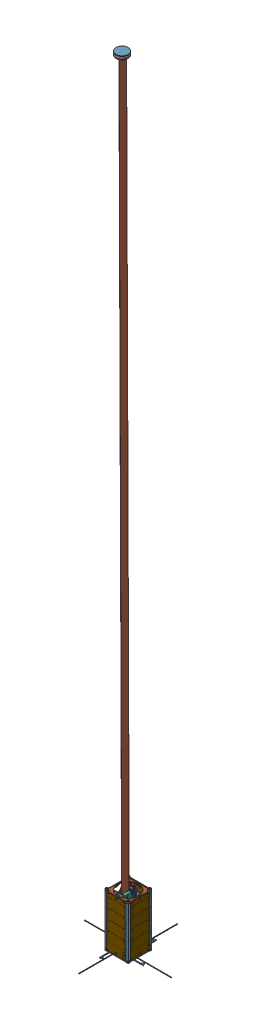
SolidWorks assembly FullAssembly_Deployed_Render, configuration Default. Lengths in mm.
Overall size (392.46 3272.78 392.43).
161 component instances, 59 part files, 152 mates.
Components (placement in the parent):
- 2U_Chassis_NoEnds-1: 2U_Chassis_NoEnds [Default] at (129.3638 156.9234 217.0115) size (100 209.95 100)
- FirstAdapterPlate-1: FirstAdapterPlate [Default] at (79.3638 3.0787 167.0115) size (95.9 1.58 90.2)
- 5-40_nut-9: 5-40_nut [90760A130] at (36.5138 -0.4932 127.0115) size (6.35 2.87 7.33)
- 5-40_nut-10: 5-40_nut [90760A130] at (36.5138 1.888 127.0115) x (-0.837169 0 -0.546944) z (-0.546944 0 0.837169) size (6.35 2.87 7.33)
- ThreadedRod_1.25mm_2-1: ThreadedRod_1.25mm_2 [94435A506] at (122.2138 23.2162 204.5115) x (0 -1 0) z (0 0 1) size (64.19 3.19 3.69)
- ThreadedRod_1.25mm_2-2: ThreadedRod_1.25mm_2 [94435A506] at (36.5138 23.2162 127.0115) x (0 -1 0) z (0 0 1) size (64.19 3.19 3.69)
- ThreadedRod_1.25mm_2-3: ThreadedRod_1.25mm_2 [94435A506] at (122.2138 23.2162 130.8115) x (0 -1 0) z (0 0 1) size (64.19 3.19 3.69)
- ThreadedRod_1.25mm_2-4: ThreadedRod_1.25mm_2 [94435A506] at (36.5138 23.2162 207.0115) x (0 -1 0) z (0 0 1) size (64.19 3.19 3.69)
- 5-40_nut-11: 5-40_nut [90760A130] at (36.5138 1.888 207.0115) x (-0.837169 0 -0.546944) z (-0.546944 0 0.837169) size (6.35 2.87 7.33)
- 5-40_nut-12: 5-40_nut [90760A130] at (36.5138 -0.4932 207.0115) x (-1 0 0) z (0 0 -1) size (6.35 2.87 7.33)
- 5-40_nut-13: 5-40_nut [90760A130] at (122.2138 14.9255 204.5115) x (0.837169 0 0.546944) z (0.546944 0 -0.837169) size (6.35 2.87 7.33)
- 5-40_nut-14: 5-40_nut [90760A130] at (122.2138 12.5443 204.5115) x (-0.540526 0 0.841327) z (-0.841327 0 -0.540526) size (6.35 2.87 7.33)
- 5-40_nut-15: 5-40_nut [90760A130] at (122.2138 14.9255 130.8115) x (0.837169 0 0.546944) z (0.546944 0 -0.837169) size (6.35 2.87 7.33)
- 5-40_nut-16: 5-40_nut [90760A130] at (122.2138 12.5443 130.8115) x (-1 0 0) z (0 0 -1) size (6.35 2.87 7.33)
- 5-40_nut-17: 5-40_nut [90760A130] at (36.5138 12.5443 207.0115) x (-1 0 0) z (0 0 -1) size (6.35 2.87 7.33)
- 5-40_nut-18: 5-40_nut [90760A130] at (36.5138 14.9255 127.0115) x (0.861208 0 0.508253) z (0.508253 0 -0.861208) size (6.35 2.87 7.33)
- 5-40_nut-19: 5-40_nut [90760A130] at (122.2138 -0.4932 204.5115) x (-1 0 0) z (0 0 -1) size (6.35 2.87 7.33)
- 5-40_nut-20: 5-40_nut [90760A130] at (36.5138 12.5443 127.0115) x (-1 0 0) z (0 0 -1) size (6.35 2.87 7.33)
- 5-40_nut-21: 5-40_nut [90760A130] at (122.2138 -0.4932 130.8115) x (-1 0 0) z (0 0 -1) size (6.35 2.87 7.33)
- 5-40_nut-22: 5-40_nut [90760A130] at (122.2138 1.888 130.8115) x (-0.837169 0 -0.546944) z (-0.546944 0 0.837169) size (6.35 2.87 7.33)
- 5-40_nut-23: 5-40_nut [90760A130] at (122.2138 1.888 204.5115) x (-0.837169 0 -0.546944) z (-0.546944 0 0.837169) size (6.35 2.87 7.33)
- 5-40_nut-24: 5-40_nut [90760A130] at (36.5138 14.9255 207.0115) x (0.837169 0 0.546944) z (0.546944 0 -0.837169) size (6.35 2.87 7.33)
- Endurosat_Internal-1: Endurosat_Internal [Default] at (43.9577 -28.9874 233.1363) x (1 0 0) z (0 1 0) size (98.18 90.37 51.86)
  - UHF_comm_type_II.STEP-1: UHF_comm_type_II.STEP [Default] at (27.1151 12.3666 -17.6788) size (97.88 89.01 26.68)
    - UHF_BOX.STEP-1: UHF_BOX.STEP [Default] at (-90.205 -23.549 76.8824) size (95 89 8.01)
    - UHF_PCB_STEP.STEP-1: UHF_PCB_STEP.STEP [Default] at (-39.659 9.6582 83.8824) size (97.88 89.01 26.68)
    - UHF_BOX-bottom-part(nif).STEP-1: UHF_BOX-bottom-part(nif).STEP [Default] at (-24.9069 125.9519 81.8824) x (1 0 0) z (0 -1 0) size (95 2.01 89)
  - OBC_EnduroSat.STEP-1: OBC_EnduroSat.STEP [Default] at (-12.5439 22.0248 80.3036) x (1 0 0) z (0 0 1) size (95 89.38 23.24)
    - SD1021117.STEP-1: SD1021117.STEP [Default] at origin size (15.2 14.1 1.88)
      - User_Library-473521001_microSD.STEP-1: User_Library-473521001_microSD.STEP [Default] at (11.4631 39.834 0.9) x (0 -1 0) z (0 0 1) size (14.1 15.2 1.88)
    - P1021117.STEP-1: P1021117.STEP [Default] at origin size (10.15 5.2 3.4)
      - MOLEX_Pico_Blade_532610471.STEP-1: MOLEX_Pico_Blade_532610471.STEP [Default] at (43.8404 79.9325 1.7) size (10.15 5.2 3.4)
        - Open CASCADE STEP translator 6.8 1.14.1.1.STEP-1: Open CASCADE STEP translator 6.8 1.14.1.1.STEP [Default] at origin size (10.15 5.2 3.4)
    - USB1021117.STEP-1: USB1021117.STEP [Default] at origin size (9.9 9.22 5.09)
      - USB_Mini_B_SMT_Horisontal.STEP-1: USB_Mini_B_SMT_Horisontal.STEP [Default] at (43.8628 84.9308 -3.6122) x (1 0 0) z (0 1 0) size (9.9 5.09 9.22)
    - U1021117.STEP-1: U1021117.STEP [Default] at origin size (25.77 25.77 1.57)
      - User_Library-LQFP176-0_5.STEP-1: User_Library-LQFP176-0_5.STEP [Default] at (45.653 34.1752 0.75) x (1 0 0) z (0 0 1) size (25.77 25.77 1.57)
    - PAN6021117.STEP-1: PAN6021117.STEP [Default] at origin size (20.15 5.2 3.5)
      - MOLEX_Pico_Blade_532611271.STEP-1: MOLEX_Pico_Blade_532611271.STEP [Default] at (74.0242 8.708 -1.6) x (-1 0 0) z (0 0 -1) size (20.15 5.2 3.5)
    - PAN5021117.STEP-1: PAN5021117.STEP [Default] at origin size (20.15 5.2 3.5)
      - MOLEX_Pico_Blade_532611271.STEP-1: MOLEX_Pico_Blade_532611271.STEP [Default] at (46.9392 8.708 -1.6) x (-1 0 0) z (0 0 -1) size (20.15 5.2 3.5)
    - PAN4021117.STEP-1: PAN4021117.STEP [Default] at origin size (20.15 5.2 3.5)
      - MOLEX_Pico_Blade_532611271.STEP-1: MOLEX_Pico_Blade_532611271.STEP [Default] at (19.8882 8.708 -1.6) x (-1 0 0) z (0 0 -1) size (20.15 5.2 3.5)
    - PAN3021117.STEP-1: PAN3021117.STEP [Default] at origin size (20.15 5.2 3.5)
      - MOLEX_Pico_Blade_532611271.STEP-1: MOLEX_Pico_Blade_532611271.STEP [Default] at (73.9902 8.708 0) x (1 0 0) z (0 0 1) size (20.15 5.2 3.5)
    - PAN2021117.STEP-1: PAN2021117.STEP [Default] at origin size (20.15 5.2 3.5)
      - MOLEX_Pico_Blade_532611271.STEP-1: MOLEX_Pico_Blade_532611271.STEP [Default] at (46.9392 8.708 0) size (20.15 5.2 3.5)
    - PAN1021117.STEP-1: PAN1021117.STEP [Default] at origin size (20.15 5.2 3.5)
      - MOLEX_Pico_Blade_532611271.STEP-1: MOLEX_Pico_Blade_532611271.STEP [Default] at (19.8882 8.708 0) size (20.15 5.2 3.5)
    - H2021117.STEP-1: H2021117.STEP [Default] at origin size (5.08 66.55 23.24)
      - Samtec-ESQ-126-14-G-D.STEP-1: Samtec-ESQ-126-14-G-D.STEP [Default] at (89.5246 43.45 2.5522) x (-1 0 0) z (0 1 0) size (5.08 23.24 66.55)
    - H1021117.STEP-1: H1021117.STEP [Default] at origin size (5.08 66.55 23.24)
      - Samtec-ESQ-126-14-G-D.STEP-1: Samtec-ESQ-126-14-G-D.STEP [Default] at (84.4446 43.45 2.5522) x (-1 0 0) z (0 1 0) size (5.08 23.24 66.55)
    - J1021117.STEP-1: J1021117.STEP [Default] at origin size (10.55 6.44 2)
      - 5040500491.STEP-1: 5040500491.STEP [Default] at (55.0672 77.863 1) x (1 0 0) z (0 0 1) size (10.55 6.44 2)
        - Open CASCADE STEP translator 6.8 1.245.1.1.STEP-1: Open CASCADE STEP translator 6.8 1.245.1.1.STEP [Default] at origin size (10.55 6.44 2)
    - JP2021117.STEP-1: JP2021117.STEP [Default] at origin size (5.56 20 4.5)
      - Samtec-TLE-110-01-G-DV.STEP-1: Samtec-TLE-110-01-G-DV.STEP [Default] at (68.9102 66.945 2.0874) x (0 1 0) z (1 0 0) size (20 4.5 5.56)
    - JP14021117.STEP-1: JP14021117.STEP [Default] at origin size (5.56 20 4.5)
      - Samtec-TLE-110-01-G-DV.STEP-1: Samtec-TLE-110-01-G-DV.STEP [Default] at (68.8848 66.945 -3.6873) x (0 1 0) z (-1 0 0) size (20 4.5 5.56)
    - JP15021117.STEP-1: JP15021117.STEP [Default] at origin size (20.15 4.2 4.7)
      - User_Library-molex_53398_1271.STEP-1: User_Library-molex_53398_1271.STEP [Default] at (19.1599 50.8269 0) x (1 0 0) z (0 0 1) size (20.15 4.2 4.7)
    - Board021117.STEP-1: Board021117.STEP [Default] at origin size (95 89.38 1.6)
  - EPS1 - Battery.STEP-1: EPS1 - Battery.STEP [Default] at (10.3437 18.3225 -33.4897) x (1 0 0) z (0 0 1) size (95.9 90.21 21.2)
    - ESQ_126_37_G_D.STEP-1: ESQ_126_37_G_D.STEP [Default] at (61.557 47.1532 82.7332) x (0 1 0) z (1 0 0) size (66.55 13.33 5.08)
      - _ESQ_126_37_G_D_socket_2.STEP-1: _ESQ_126_37_G_D_socket_2.STEP [Default] at (-33.274 0 0) size (66.55 8.51 4.95)
      - _ESQ_126_37_G_D_pins_4.STEP-1: _ESQ_126_37_G_D_pins_4.STEP [Default] at origin size (65.79 9.77 4.7)
      - _ESQ_126_37_G_D_LL_bpins_6.STEP-1: _ESQ_126_37_G_D_LL_bpins_6.STEP [Default] at (-33.147 -2.54 0) size (66.04 2.54 5.08)
    - ESQ_126_37_G_D.STEP-2: ESQ_126_37_G_D.STEP [Default] at (66.637 47.1532 82.7332) x (0 1 0) z (1 0 0) size (66.55 13.33 5.08)
      - _ESQ_126_37_G_D_socket_2.STEP-1: _ESQ_126_37_G_D_socket_2.STEP [Default] at (-33.274 0 0) size (66.55 8.51 4.95)
      - _ESQ_126_37_G_D_pins_4.STEP-1: _ESQ_126_37_G_D_pins_4.STEP [Default] at origin size (65.79 9.77 4.7)
      - _ESQ_126_37_G_D_LL_bpins_6.STEP-1: _ESQ_126_37_G_D_LL_bpins_6.STEP [Default] at (-33.147 -2.54 0) size (66.04 2.54 5.08)
    - ES_EPS_Rev1_4_PCB_STEP.STEP-1: ES_EPS_Rev1_4_PCB_STEP.STEP [Default] at (-22.8876 2.7023 80.1932) size (95.9 90.21 13.97)
    - top-cover_EPS1.STEP-1: top-cover_EPS1.STEP [Default] at (-22.8876 2.7023 80.1932) size (95.9 90.2 14)
    - bottom-cover_Rev1.2.STEP-1: bottom-cover_Rev1.2.STEP [Default] at (25.0624 47.8023 72.9932) size (95.9 90.2 13.5)
    - TR Fastenings Ltd-M2_5X4mm.STEP-1: TR Fastenings Ltd-M2_5X4mm.STEP [Default] at (-22.8876 68.8523 83.4832) x (0 0.841973 -0.539519) z (-1 0 0) size (4.7 4.7 4)
    - TR Fastenings Ltd-M2_5X4mm.STEP-2: TR Fastenings Ltd-M2_5X4mm.STEP [Default] at (-22.8876 26.7523 83.4832) x (0 0.924225 0.381849) z (-1 0 0) size (4.7 4.7 4)
    - 965 M3x6 Torx_M3X6mm.STEP-1: 965 M3x6 Torx_M3X6mm.STEP [Default] at (54.8324 9.3023 93.4576) x (0.993054 -0.117656 0) z (0 0 1) size (5.5 5.5 6)
    - 965 M3x6 Torx_M3X6mm.STEP-2: 965 M3x6 Torx_M3X6mm.STEP [Default] at (54.8324 77.0023 93.4697) x (0.987647 0.156698 0) z (0 0 1) size (5.5 5.5 6)
- ThreadedRodAdapter-1: ThreadedRodAdapter [Default] at (122.2283 76.3162 204.4864) x (1 0 0) z (0 0 -1) size (6 20 5.2)
- ThreadedRodAdapter-2: ThreadedRodAdapter [Default] at (36.5283 76.3162 206.9864) x (1 0 0) z (0 0 -1) size (6 20 5.2)
- ThreadedRodAdapter-3: ThreadedRodAdapter [Default] at (122.2397 76.3162 130.7984) x (0.837169 0 0.546944) z (0.546944 0 -0.837169) size (6 20 5.2)
- ThreadedRodAdapter-4: ThreadedRodAdapter [Default] at (36.5283 76.3162 126.9864) x (1 0 0) z (0 0 -1) size (6 20 5.2)
- M4_ThreadedRod_Shortened-1: M4_ThreadedRod_Shortened [99055A110] at (122.2138 65.5162 204.5115) x (0 -1 0) z (-0.991936 0 -0.126738) size (42.53 3.77 4.24)
- M4_ThreadedRod_Shortened-2: M4_ThreadedRod_Shortened [99055A110] at (36.5138 65.5162 127.0115) x (0 -1 0) z (0.9699 0 -0.243505) size (42.53 3.77 4.24)
- M4_ThreadedRod_Shortened-3: M4_ThreadedRod_Shortened [99055A110] at (36.5138 65.5162 207.0115) x (0 -1 0) z (-0.548354 0 0.836246) size (42.53 3.77 4.24)
- M4_ThreadedRod_Shortened-4: M4_ThreadedRod_Shortened [99055A110] at (122.2138 65.5162 130.8115) x (0 -1 0) z (0.930349 0 -0.366676) size (42.53 3.77 4.24)
- CustomMagnetorquer-1: CustomMagnetorquer [Default] at (79.43 83.3162 167.0978) x (1 0 0.000843) z (-0.000843 0 1) size (95.9 29.64 90.3)
- 5-40_nut-25: 5-40_nut [90760A130] at (122.2138 86.1468 130.8115) x (0.837169 0 0.546944) z (0.546944 0 -0.837169) size (6.35 2.87 7.33)
- 5-40_nut-27: 5-40_nut [90760A130] at (36.5138 86.1468 127.0115) x (0.837169 0 0.546944) z (0.546944 0 -0.837169) size (6.35 2.87 7.33)
- 5-40_nut-28: 5-40_nut [90760A130] at (122.2138 86.1468 204.5115) x (0.837169 0 0.546944) z (0.546944 0 -0.837169) size (6.35 2.87 7.33)
- 5-40_nut-29: 5-40_nut [90760A130] at (36.5138 86.1468 207.0115) x (0.837169 0 0.546944) z (0.546944 0 -0.837169) size (6.35 2.87 7.33)
- Large_Aperature_Base_Plate.step-1: Large_Aperature_Base_Plate.step [Default] at (79.3638 206.6734 167.0115) x (-1 0 0) z (0 0 1) size (100 47.85 100)
- M4_Hex_Screw-1: M4_Hex_Screw [93635A104] at (121.3138 103.5762 167.0115) x (0 -1 0) z (-0.969186 0 0.24633) size (11.04 8.08 7)
- M4_Hex_Screw-2: M4_Hex_Screw [93635A104] at (37.4138 103.5762 167.0115) x (0 -1 0) z (-0.962943 0 -0.269706) size (11.04 8.08 7)
- M4_Hex_Screw-3: M4_Hex_Screw [93635A104] at (79.3638 103.5762 206.1115) x (0 -1 0) z (0.946217 0 0.323534) size (11.04 8.08 7)
- M4_Hex_Screw-4: M4_Hex_Screw [93635A104] at (79.3638 103.5762 127.9115) x (0 -1 0) z (-0.57376 0 0.819023) size (11.04 8.08 7)
- M4_Nut-1: M4_Nut [90710A035] at (37.4138 101.9162 167.0115) x (-0.396266 0 0.918136) z (-0.918136 0 -0.396266) size (7 2.75 8.08)
- M4_Nut-2: M4_Nut [90710A035] at (121.3138 101.9162 167.0115) x (-0.143588 0 0.989638) z (-0.989638 0 -0.143588) size (7 2.75 8.08)
- M4_Nut-3: M4_Nut [90710A035] at (79.3638 101.9162 206.1115) x (0.569583 0 0.821934) z (-0.821934 0 0.569583) size (7 2.75 8.08)
- M4_Nut-4: M4_Nut [90710A035] at (79.3638 101.9162 127.9115) x (0.466483 0 0.88453) z (-0.88453 0 0.466483) size (7 2.75 8.08)
- SecondAdapterPlate.1-3: SecondAdapterPlate.1 [Default] at (79.3638 104.5962 167.0115) x (1 0 0) z (0 0 -1) size (95.9 7.58 93.2)
- SecondAdapterPlate.2-2: SecondAdapterPlate.2 [Default] at (79.3638 104.5962 167.0115) x (-1 0 0) z (0 0 -1) size (95.9 7.58 93.2)
- SolarPanel_Clips.step-1: SolarPanel_Clips.step [Default] at (79.3624 -5.9176 167.0102) size (102.54 4.45 102.54)
- CoverPlate_Corners-2: CoverPlate_Corners [Default] at (79.3624 -4.6756 167.0102) x (1 0 0) z (0 1 0) size (99.75 99.75 8.54)
- SolarPanel_Clips.step-2: SolarPanel_Clips.step [Default] at (79.3638 206.6734 167.0115) x (1 0 0) z (0 0 -1) size (102.54 4.45 102.54)
- SolarPanel_2U_Side_Pumpkin.step-1: SolarPanel_2U_Side_Pumpkin.step [Default] at (79.3638 100.1605 216.9861) x (1 0 0) z (0 -1 0) size (82.55 6.14 214)
- SolarPanel_2U_Side_Pumpkin.step-2: SolarPanel_2U_Side_Pumpkin.step [Default] at (129.3384 100.1605 167.0115) x (0 0 -1) z (0 -1 0) size (82.55 6.14 214)
- SolarPanel_2U_Side_Pumpkin.step-4: SolarPanel_2U_Side_Pumpkin.step [Default] at (79.3638 100.1605 117.0369) x (-1 0 0) z (0 -1 0) size (82.55 6.14 214)
- M_CoverPlate_Custom_Cut-1: M_CoverPlate_Custom_Cut [Default] at (79.3638 -6.3266 167.0115) size (100 14 100)
- M_ThreadedRod_1.25mm_1-1: M_ThreadedRod_1.25mm_1 [94435A506] at (49.3638 -30.8026 197.0115) x (0 -1 0) z (0 0 1) size (12.66 3.22 3.67)
- M_ThreadedRod_1.25mm_1-2: M_ThreadedRod_1.25mm_1 [94435A506] at (109.3638 -30.8026 197.0115) x (0 -1 0) z (0 0 1) size (12.66 3.22 3.67)
- M_ThreadedRod_1.25mm_1-3: M_ThreadedRod_1.25mm_1 [94435A506] at (49.3638 -30.8026 137.0115) x (0 -1 0) z (0 0 1) size (12.66 3.22 3.67)
- M_ThreadedRod_1.25mm_1-4: M_ThreadedRod_1.25mm_1 [94435A506] at (109.3638 -30.8026 137.0115) x (0 -1 0) z (0 0 1) size (12.66 3.22 3.67)
- 5-40_nut-30: 5-40_nut [90760A130] at (49.3638 1.888 137.0115) x (-0.837169 0 -0.546944) z (-0.546944 0 0.837169) size (6.35 2.87 7.33)
- 5-40_nut-31: 5-40_nut [90760A130] at (49.3638 1.888 197.0115) size (6.35 2.87 7.33)
- 5-40_nut-32: 5-40_nut [90760A130] at (109.3638 1.888 137.0115) size (6.35 2.87 7.33)
- 5-40_nut-33: 5-40_nut [90760A130] at (109.3638 5.8493 137.0115) x (-0.837169 0 -0.546944) z (-0.546944 0 0.837169) size (6.35 2.87 7.33)
- 5-40_nut-34: 5-40_nut [90760A130] at (109.3638 5.8493 197.0115) size (6.35 2.87 7.33)
- 5-40_nut-35: 5-40_nut [90760A130] at (109.3638 1.888 197.0115) size (6.35 2.87 7.33)
- 5-40_nut-36: 5-40_nut [90760A130] at (49.3638 5.8493 197.0115) size (6.35 2.87 7.33)
- 5-40_nut-37: 5-40_nut [90760A130] at (49.3638 5.8493 137.0115) size (6.35 2.87 7.33)
- M_M3_ThreadedRod-1: M_M3_ThreadedRod [Default] at (80.7505 116.7916 150.1828) x (0 1 0) z (0 0 1) size (101.43 3.04 3.46)
  - 90024A220_18-8 STAINLESS STEEL THREADED ROD-1: 90024A220_18-8 STAINLESS STEEL THREADED ROD [90024A220] at (26.8845 38.7417 59.6923) size (75.94 3.04 3.46)
  - 90024A220_18-8 STAINLESS STEEL THREADED ROD-2: 90024A220_18-8 STAINLESS STEEL THREADED ROD [90024A220] at (52.3745 38.7417 59.6923) size (75.94 3.04 3.46)
- M_M3_ThreadedRod-2: M_M3_ThreadedRod [Default] at (118.4438 196.0507 52.987) x (0 -1 0) z (-0.546944 0 0.837169) size (101.43 3.04 3.46)
  - 90024A220_18-8 STAINLESS STEEL THREADED ROD-1: 90024A220_18-8 STAINLESS STEEL THREADED ROD [90024A220] at (26.8845 38.7417 59.6923) size (75.94 3.04 3.46)
  - 90024A220_18-8 STAINLESS STEEL THREADED ROD-2: 90024A220_18-8 STAINLESS STEEL THREADED ROD [90024A220] at (52.3745 38.7417 59.6923) size (75.94 3.04 3.46)
- M_M3_ThreadedRod-3: M_M3_ThreadedRod [Default] at (115.9038 196.0507 138.712) x (0 -1 0) z (-0.546944 0 0.837169) size (101.43 3.04 3.46)
  - 90024A220_18-8 STAINLESS STEEL THREADED ROD-1: 90024A220_18-8 STAINLESS STEEL THREADED ROD [90024A220] at (26.8845 38.7417 59.6923) size (75.94 3.04 3.46)
  - 90024A220_18-8 STAINLESS STEEL THREADED ROD-2: 90024A220_18-8 STAINLESS STEEL THREADED ROD [90024A220] at (52.3745 38.7417 59.6923) size (75.94 3.04 3.46)
- M_M3_ThreadedRod-4: M_M3_ThreadedRod [Default] at (38.4338 196.0507 52.987) x (0 -1 0) z (-0.546944 0 0.837169) size (101.43 3.04 3.46)
  - 90024A220_18-8 STAINLESS STEEL THREADED ROD-1: 90024A220_18-8 STAINLESS STEEL THREADED ROD [90024A220] at (26.8845 38.7417 59.6923) size (75.94 3.04 3.46)
  - 90024A220_18-8 STAINLESS STEEL THREADED ROD-2: 90024A220_18-8 STAINLESS STEEL THREADED ROD [90024A220] at (52.3745 38.7417 59.6923) size (75.94 3.04 3.46)
- Sprocket Prototype 9 (1)-1: Sprocket Prototype 9 (1) [Extended] at (39.2583 166.9952 186.3315) size (104.72 3149.47 80.29)
  - Combined Side Plate Left 9 (1)-1: Combined Side Plate Left 9 (1) [Default] at origin size (88.84 86.77 8.42)
  - 5972K222_BALL BEARING 9 (1)-1: 5972K222_BALL BEARING 9 (1) [5972K222] at (20 15 3.5) size (22 22 7)
  - Back Plate 9 (1)-1: Back Plate 9 (1) [Default] at (44.6711 0 -29.85) x (0 0 1) z (-1 0 0) size (29.85 30 12.5)
  - Custom Axle Sprocket 9 (1)-1: Custom Axle Sprocket 9 (1) [6 tooth BD] at (20 15 -37.45) size (30 45.38 45.05)
  - 5972K222_BALL BEARING 9 (1)-2: 5972K222_BALL BEARING 9 (1) [5972K222] at (20 15 -33.35) x (-0.381749 -0.924266 0) z (0 0 1) size (22 22 7)
  - Motor Mount 9 (1)-1: Motor Mount 9 (1) [Default] at (12.4 21.5 -57.025) x (-1 0 0) z (0 0 1) size (53.75 30 20.17)
  - Pololu Motor 9 (1)-1: Pololu Motor 9 (1) [Default] at (20 15 -47.05) x (0 0 1) z (1 0 0) size (39.27 10 12)
  - Combined Side Plate Right 9 (1)-1: Combined Side Plate Right 9 (1) [Default] at (0 0 -9.85) size (88.84 86.77 8.42)
  - Fake Tape Measure (1)-1: Fake Tape Measure (1) [Extended] at (60.5 -28.3845 -37.375) x (0.999993 0.00369 0) z (0 0 1) size (56.9 3134.25 43)
  - Tip Mass-1: Tip Mass [Default] at (-18.3297 3053.0787 8.8247) x (-0.124999 -0.000461 -0.992157) z (0.99215 0.003661 -0.125) size (51 15 51)
    - Tip Mass Bottom Plate (1)-1: Tip Mass Bottom Plate (1) [Default] at (20.4018 24.2669 38.6628) x (1 0 0) z (0 1 0) size (51 51 4)
    - Tip Mass Side Wall (1)-1: Tip Mass Side Wall (1) [Default] at (20.4018 37.2669 38.6628) x (1 0 0) z (0 -1 0) size (51 51 11)
    - Tip Mass Top Plate (1)-1: Tip Mass Top Plate (1) [Default] at (20.4018 39.2669 38.6628) x (1 0 0) z (0 -1 0) size (51 51 4)
- EnduroSat_UHF_antenna_deployed.STEP-1: EnduroSat_UHF_antenna_deployed.STEP [Default] at (96.7621 -3.9243 155.0709) x (1 0 0) z (0 -1 0) size (392.46 392.43 12.2)
  - ES_UHF_Ant_v6_1_Upper.STEP-1: ES_UHF_Ant_v6_1_Upper.STEP [Default] at (-18.0478 12.2483 3.4137) size (98 98 0.5)
  - rod_holder_13042016.STEP-1: rod_holder_13042016.STEP [Default] at (-270.694 -22.9234 2.9114) size (8 4 3)
  - rod_holder_13042016.STEP-2: rod_holder_13042016.STEP [Default] at (-200.194 7.4516 2.9114) size (8 4 3)
  - rod_holder_13042016.STEP-3: rod_holder_13042016.STEP [Default] at (-13.2511 264.8944 5.9114) x (0 -1 0) z (0 0 -1) size (8 4 3)
  - rod_holder_13042016.STEP-4: rod_holder_13042016.STEP [Default] at (17.1489 -240.4229 2.9114) x (0 1 0) z (0 0 1) size (8 4 3)
  - rod.STEP-1: rod.STEP [Default] at (-31.1978 43.4483 5.9114) x (1 0 0) z (0 1 0) size (0.2 3 165)
  - rod_1.STEP-1: rod_1.STEP [Default] at (-4.9978 -18.9767 2.9114) x (1 0 0) z (0 -1 0) size (0.2 3 165)
  - rod_2.STEP-1: rod_2.STEP [Default] at (178.2522 25.3983 2.9114) x (0 -1 0) z (-1 0 0) size (0.2 3 165)
  - rod_3.STEP-1: rod_3.STEP [Default] at (-214.2084 -0.9767 2.9114) x (0 1 0) z (1 0 0) size (0.2 3 165)
  - ES_UHF_Top_v6.STEP-1: ES_UHF_Top_v6.STEP [Default] at (-18.0467 12.2583 8.1051) size (98 98 1.69)
  - ES_UHF_Ant_Feed_v6_1_nc.STEP-1: ES_UHF_Ant_Feed_v6_1_nc.STEP [Default] at (-18.0467 12.2583 2.9114) size (98 98 8.25)
  - opened_doors_fb.STEP-1: opened_doors_fb.STEP [Default] at (-3.8964 12.7729 -3.5178) x (1 0 0) z (0 0 1) size (184.26 184.26 3.41)
Mates (geometry in assembly coordinates):
- Coincident13: coincident anti-aligned: plane of 5-40_nut-9 through (33.3388 0.6974 125.1785) normal (0 1 0); plane of 5-40_nut-10 through (40.1744 0.6974 127.2135) normal (0 -1 0)
- Concentric15: concentric aligned: circle of 5-40_nut-9; circle of 5-40_nut-10
- Concentric20: concentric aligned: circle of 5-40_nut-11; circle of 5-40_nut-12
- Coincident19: coincident anti-aligned: plane of 5-40_nut-11 through (40.1744 0.6974 207.2135) normal (0 -1 0); plane of 5-40_nut-12 through (39.6888 0.6974 208.8446) normal (0 1 0)
- Concentric21: concentric aligned: circle of 5-40_nut-13; circle of 5-40_nut-14
- Coincident20: coincident anti-aligned: plane of 5-40_nut-13 through (118.5532 13.7349 204.3096) normal (0 -1 0); plane of 5-40_nut-14 through (125.4722 13.7349 202.8312) normal (0 1 0)
- Concentric22: concentric aligned: circle of 5-40_nut-15; circle of 5-40_nut-16
- Coincident21: coincident anti-aligned: plane of 5-40_nut-15 through (118.5532 13.7349 130.6096) normal (0 -1 0); plane of 5-40_nut-16 through (125.3888 13.7349 132.6446) normal (0 1 0)
- Concentric23: concentric aligned: circle of 5-40_nut-19; circle of 5-40_nut-23
- Coincident22: coincident anti-aligned: plane of 5-40_nut-19 through (125.3888 0.6974 206.3446) normal (0 1 0); plane of 5-40_nut-23 through (125.8744 0.6974 204.7135) normal (0 -1 0)
- Concentric24: concentric aligned: circle of 5-40_nut-21; circle of 5-40_nut-22
- Coincident23: coincident anti-aligned: plane of 5-40_nut-21 through (125.3888 0.6974 132.6446) normal (0 1 0); plane of 5-40_nut-22 through (125.8744 0.6974 131.0135) normal (0 -1 0)
- Coincident24: coincident anti-aligned: plane of 5-40_nut-18 through (32.8478 13.7349 126.9765) normal (0 -1 0); plane of 5-40_nut-20 through (39.6888 13.7349 128.8446) normal (0 1 0)
- Concentric25: concentric aligned: circle of 5-40_nut-18; circle of 5-40_nut-20
- Coincident25: coincident anti-aligned: plane of 5-40_nut-17 through (39.6888 13.7349 208.8446) normal (0 1 0); plane of 5-40_nut-24 through (32.8532 13.7349 206.8096) normal (0 -1 0)
- Concentric26: concentric aligned: circle of 5-40_nut-17; circle of 5-40_nut-24
- Coincident26: coincident anti-aligned: plane of FirstAdapterPlate-1 through (79.3638 3.0787 167.0115) normal (0 -1 0); plane of 5-40_nut-22 through (125.8744 3.0787 131.0135) normal (0 1 0)
- Coincident27: coincident anti-aligned: plane of FirstAdapterPlate-1 through (79.3638 3.0787 167.0115) normal (0 -1 0); plane of 5-40_nut-10 through (40.1744 3.0787 127.2135) normal (0 1 0)
- Coincident28: coincident anti-aligned: plane of FirstAdapterPlate-1 through (79.3638 3.0787 167.0115) normal (0 -1 0); plane of 5-40_nut-11 through (40.1744 3.0787 207.2135) normal (0 1 0)
- Coincident29: coincident anti-aligned: plane of FirstAdapterPlate-1 through (79.3638 3.0787 167.0115) normal (0 -1 0); plane of 5-40_nut-23 through (125.8744 3.0787 204.7135) normal (0 1 0)
- Concentric27: concentric anti-aligned: circle of FirstAdapterPlate-1; circle of 5-40_nut-12
- Concentric28: concentric aligned: circle of FirstAdapterPlate-1; circle of 5-40_nut-21
- Concentric29: concentric anti-aligned: circle of FirstAdapterPlate-1; circle of 5-40_nut-9
- Concentric30: concentric anti-aligned: circle of FirstAdapterPlate-1; circle of 5-40_nut-19
- Coincident31: coincident aligned: plane of ThreadedRod_1.25mm_2-1 through (122.2138 -1.6838 204.5115) normal (0 -1 0); plane of 5-40_nut-19 through (125.3888 -1.6838 206.3446) normal (0 -1 0)
- Concentric31: concentric anti-aligned: circle of ThreadedRod_1.25mm_2-1; circle of 5-40_nut-19
- Coincident32: coincident aligned: plane of ThreadedRod_1.25mm_2-3 through (122.2138 -1.6838 130.8115) normal (0 -1 0); plane of 5-40_nut-21 through (125.3888 -1.6838 132.6446) normal (0 -1 0)
- Concentric32: concentric anti-aligned: circle of ThreadedRod_1.25mm_2-3; circle of 5-40_nut-21
- Coincident33: coincident aligned: plane of ThreadedRod_1.25mm_2-4 through (36.5138 -1.6838 207.0115) normal (0 -1 0); plane of 5-40_nut-12 through (39.6888 -1.6838 208.8446) normal (0 -1 0)
- Concentric33: concentric anti-aligned: circle of ThreadedRod_1.25mm_2-4; circle of 5-40_nut-12
- Coincident34: coincident aligned: plane of 5-40_nut-9 through (33.3388 -1.6838 125.1785) normal (0 -1 0); plane of ThreadedRod_1.25mm_2-2 through (36.5138 -1.6838 127.0115) normal (0 -1 0)
- Concentric34: concentric anti-aligned: circle of 5-40_nut-9; circle of ThreadedRod_1.25mm_2-2
- Concentric36: concentric anti-aligned: circle of ThreadedRod_1.25mm_2-4; circle of 5-40_nut-17
- Concentric37: concentric anti-aligned: circle of ThreadedRod_1.25mm_2-2; circle of 5-40_nut-20
- Concentric38: concentric anti-aligned: circle of ThreadedRod_1.25mm_2-3; circle of 5-40_nut-16
- Concentric39: concentric anti-aligned: circle of ThreadedRod_1.25mm_2-1; circle of 5-40_nut-14
- Concentric40: concentric anti-aligned: circle of ThreadedRod_1.25mm_2-2; circle of Endurosat_Internal-1/OBC_EnduroSat.STEP-1/Board021117.STEP-1
- Concentric41: concentric anti-aligned: circle of 5-40_nut-13; circle of Endurosat_Internal-1/OBC_EnduroSat.STEP-1/Board021117.STEP-1
- Coincident40: coincident anti-aligned: plane of 5-40_nut-13 through (118.5532 16.1162 204.3096) normal (0 1 0); plane of Endurosat_Internal-1/EPS1 - Battery.STEP-1/ES_EPS_Rev1_4_PCB_STEP.STEP-1 through (31.4138 16.1162 212.1115) normal (0 -1 0)
- Coincident42: coincident anti-aligned: plane of 5-40_nut-15 through (118.5532 16.1162 130.6096) normal (0 1 0); plane of Endurosat_Internal-1/EPS1 - Battery.STEP-1/ES_EPS_Rev1_4_PCB_STEP.STEP-1 through (31.4138 16.1162 212.1115) normal (0 -1 0)
- Coincident43: coincident anti-aligned: plane of 5-40_nut-18 through (32.8478 16.1162 126.9765) normal (0 1 0); plane of Endurosat_Internal-1/EPS1 - Battery.STEP-1/ES_EPS_Rev1_4_PCB_STEP.STEP-1 through (31.4138 16.1162 212.1115) normal (0 -1 0)
- Coincident44: coincident anti-aligned: plane of 5-40_nut-24 through (32.8532 16.1162 206.8096) normal (0 1 0); plane of Endurosat_Internal-1/EPS1 - Battery.STEP-1/ES_EPS_Rev1_4_PCB_STEP.STEP-1 through (31.4138 16.1162 212.1115) normal (0 -1 0)
- Concentric46: concentric anti-aligned: circle of ThreadedRod_1.25mm_2-1; circle of ThreadedRodAdapter-1
- Distance6: distance = 10 mm aligned: plane of ThreadedRod_1.25mm_2-1 through (122.2138 61.3162 204.5115) normal (0 1 0); plane of ThreadedRodAdapter-1 through (122.2283 71.3162 204.4864) normal (0 1 0)
- Concentric47: concentric anti-aligned: circle of ThreadedRod_1.25mm_2-3; circle of ThreadedRodAdapter-3
- Distance7: distance = 10 mm aligned: plane of ThreadedRodAdapter-3 through (122.2397 71.3162 130.7984) normal (0 1 0); plane of ThreadedRod_1.25mm_2-3 through (122.2138 61.3162 130.8115) normal (0 1 0)
- Concentric48: concentric anti-aligned: circle of ThreadedRod_1.25mm_2-4; circle of ThreadedRodAdapter-2
- Distance8: distance = 10 mm aligned: plane of ThreadedRod_1.25mm_2-4 through (36.5138 61.3162 207.0115) normal (0 1 0); plane of ThreadedRodAdapter-2 through (36.5283 71.3162 206.9864) normal (0 1 0)
- Concentric49: concentric anti-aligned: circle of ThreadedRod_1.25mm_2-2; circle of ThreadedRodAdapter-4
- Distance9: distance = 10 mm aligned: plane of ThreadedRod_1.25mm_2-2 through (36.5138 61.3162 127.0115) normal (0 1 0); plane of ThreadedRodAdapter-4 through (36.5283 71.3162 126.9864) normal (0 1 0)
- Concentric50: concentric aligned: circle of ThreadedRodAdapter-1; circle of M4_ThreadedRod_Shortened-1
- Distance10: distance = 10 mm anti-aligned: plane of M4_ThreadedRod_Shortened-1 through (122.2138 61.3162 204.5115) normal (0 -1 0); plane of ThreadedRodAdapter-1 through (122.2283 71.3162 204.4864) normal (0 1 0)
- Concentric51: concentric aligned: circle of ThreadedRodAdapter-2; circle of M4_ThreadedRod_Shortened-3
- Coincident46: coincident anti-aligned: plane of ThreadedRod_1.25mm_2-4 through (36.5138 61.3162 207.0115) normal (0 1 0); plane of M4_ThreadedRod_Shortened-3 through (36.5138 61.3162 207.0115) normal (0 -1 0)
- Concentric52: concentric aligned: circle of ThreadedRodAdapter-3; circle of M4_ThreadedRod_Shortened-4
- Coincident47: coincident anti-aligned: plane of ThreadedRod_1.25mm_2-3 through (122.2138 61.3162 130.8115) normal (0 1 0); plane of M4_ThreadedRod_Shortened-4 through (122.2138 61.3162 130.8115) normal (0 -1 0)
- Concentric53: concentric aligned: circle of ThreadedRodAdapter-4; circle of M4_ThreadedRod_Shortened-2
- Coincident48: coincident anti-aligned: plane of ThreadedRod_1.25mm_2-2 through (36.5138 61.3162 127.0115) normal (0 1 0); plane of M4_ThreadedRod_Shortened-2 through (36.5138 61.3162 127.0115) normal (0 -1 0)
- Concentric60: concentric anti-aligned: circle of M4_ThreadedRod_Shortened-2; circle of CustomMagnetorquer-1
- Coincident51: coincident anti-aligned: plane of ThreadedRodAdapter-2 through (36.5283 71.3162 206.9864) normal (0 1 0); plane of CustomMagnetorquer-1 through (79.43 71.3162 167.0978) normal (0 -1 0)
- Concentric63: concentric aligned: circle of M4_ThreadedRod_Shortened-3; circle of 5-40_nut-29
- Coincident52: coincident anti-aligned: plane of CustomMagnetorquer-1 through (79.43 84.9562 167.0978) normal (0 1 0); plane of 5-40_nut-29 through (32.8532 84.9562 206.8096) normal (0 -1 0)
- Concentric64: concentric aligned: circle of M4_ThreadedRod_Shortened-2; circle of 5-40_nut-27
- Coincident53: coincident anti-aligned: plane of CustomMagnetorquer-1 through (79.43 84.9562 167.0978) normal (0 1 0); plane of 5-40_nut-27 through (32.8532 84.9562 126.8096) normal (0 -1 0)
- Concentric65: concentric aligned: circle of M4_ThreadedRod_Shortened-1; circle of 5-40_nut-28
- Coincident54: coincident anti-aligned: plane of CustomMagnetorquer-1 through (79.43 84.9562 167.0978) normal (0 1 0); plane of 5-40_nut-28 through (118.5532 84.9562 204.3096) normal (0 -1 0)
- Concentric66: concentric aligned: circle of M4_ThreadedRod_Shortened-4; circle of 5-40_nut-25
- Coincident55: coincident anti-aligned: plane of CustomMagnetorquer-1 through (79.43 84.9562 167.0978) normal (0 1 0); plane of 5-40_nut-25 through (118.5532 84.9562 130.6096) normal (0 -1 0)
- Concentric86: concentric aligned: circle of 2U_Chassis_NoEnds-1; circle of Large_Aperature_Base_Plate.step-1
- Concentric87: concentric aligned: circle of 2U_Chassis_NoEnds-1; circle of Large_Aperature_Base_Plate.step-1
- Concentric88: concentric aligned: circle of M4_ThreadedRod_Shortened-4; circle of SecondAdapterPlate.1-3
- Coincident110: coincident anti-aligned: plane of M4_ThreadedRod_Shortened-2 through (36.5138 103.0162 127.0115) normal (0 1 0); plane of SecondAdapterPlate.1-3 through (79.3638 103.0162 167.0115) normal (0 -1 0)
- Concentric89: concentric aligned: circle of M4_ThreadedRod_Shortened-2; circle of SecondAdapterPlate.1-3
- Coincident114: coincident anti-aligned: plane of M4_Hex_Screw-3 through (75.3983 106.1762 206.8912) normal (0 -1 0); plane of SecondAdapterPlate.2-2 through (79.3638 106.1762 167.0115) normal (0 1 0)
- Concentric94: concentric aligned: circle of M4_Hex_Screw-3; circle of SecondAdapterPlate.2-2
- Coincident115: coincident anti-aligned: plane of M4_Nut-4 through (79.5185 103.0162 123.8731) normal (0 1 0); plane of SecondAdapterPlate.1-3 through (79.3638 103.0162 167.0115) normal (0 -1 0)
- Concentric95: concentric aligned: circle of M4_Nut-4; circle of SecondAdapterPlate.1-3
- Coincident116: coincident anti-aligned: plane of M4_Hex_Screw-1 through (124.2082 106.1762 164.1909) normal (0 -1 0); plane of SecondAdapterPlate.2-2 through (79.3638 106.1762 167.0115) normal (0 1 0)
- Concentric96: concentric aligned: circle of M4_Hex_Screw-1; circle of SecondAdapterPlate.2-2
- Coincident117: coincident anti-aligned: plane of M4_Nut-1 through (40.656 103.0162 164.5988) normal (0 1 0); plane of SecondAdapterPlate.1-3 through (79.3638 103.0162 167.0115) normal (0 -1 0)
- Concentric97: concentric aligned: circle of M4_Nut-1; circle of SecondAdapterPlate.1-3
- Concentric98: concentric aligned: circle of M4_Hex_Screw-2; circle of SecondAdapterPlate.2-2
- Coincident118: coincident anti-aligned: plane of M4_Hex_Screw-2 through (41.3291 106.1762 166.0097) normal (0 -1 0); plane of SecondAdapterPlate.2-2 through (79.3638 106.1762 167.0115) normal (0 1 0)
- Concentric99: concentric aligned: circle of M4_Nut-2; circle of SecondAdapterPlate.1-3
- Coincident119: coincident anti-aligned: plane of M4_Nut-2 through (123.8161 103.0162 163.838) normal (0 1 0); plane of SecondAdapterPlate.1-3 through (79.3638 103.0162 167.0115) normal (0 -1 0)
- Concentric100: concentric aligned: circle of M4_Hex_Screw-4; circle of SecondAdapterPlate.2-2
- Coincident120: coincident anti-aligned: plane of M4_Hex_Screw-4 through (79.7169 106.1762 123.8856) normal (0 -1 0); plane of SecondAdapterPlate.2-2 through (79.3638 106.1762 167.0115) normal (0 1 0)
- Coincident121: coincident anti-aligned: plane of M4_Nut-3 through (79.0312 103.0162 202.0838) normal (0 1 0); plane of SecondAdapterPlate.1-3 through (79.3638 103.0162 167.0115) normal (0 -1 0)
- Concentric101: concentric aligned: circle of M4_Nut-3; circle of SecondAdapterPlate.1-3
- Coincident126: coincident anti-aligned: plane of SecondAdapterPlate.1-3 through (79.3638 104.5962 167.0115) normal (0 1 0); plane of SecondAdapterPlate.2-2 through (79.3638 104.5962 167.0115) normal (0 -1 0)
- Coincident127: coincident anti-aligned: circle of SecondAdapterPlate.1-3; circle of SecondAdapterPlate.2-2
- Coincident128: coincident anti-aligned: circle of SecondAdapterPlate.1-3; circle of SecondAdapterPlate.2-2
- Concentric109: concentric aligned: circle of SolarPanel_Clips.step-1; circle of CoverPlate_Corners-2
- Coincident131: coincident anti-aligned: plane of 2U_Chassis_NoEnds-1 through (31.3958 -4.8026 214.9795) normal (0 -1 0); plane of CoverPlate_Corners-2 through (32.1945 -4.8026 214.1781) normal (0 1 0)
- Concentric111: concentric anti-aligned: circle of Large_Aperature_Base_Plate.step-1; circle of SolarPanel_Clips.step-2
- Coincident136: coincident anti-aligned: plane of Large_Aperature_Base_Plate.step-1 through (127.9668 206.6734 118.4085) normal (0 1 0); plane of SolarPanel_Clips.step-2 through (110.0493 206.6734 217.0115) normal (0 -1 0)
- Parallel3: parallel anti-aligned: plane of 2U_Chassis_NoEnds-1 through (129.3638 89.17 315.1419) normal (1 0 0); plane of SolarPanel_Clips.step-2 through (130.1258 207.1814 212.6209) normal (-1 0 0)
- Concentric112: concentric anti-aligned: circle of 2U_Chassis_NoEnds-1; circle of SolarPanel_2U_Side_Pumpkin.step-1
- Coincident138: coincident anti-aligned: plane of SolarPanel_Clips.step-2 through (33.7545 207.1814 217.7735) normal (0 0 -1); plane of SolarPanel_2U_Side_Pumpkin.step-1 through (79.3638 100.1605 217.7735) normal (0 0 1)
- Parallel4: parallel aligned: line of SolarPanel_Clips.step-2 through (120.4992 203.727 218.2815) axis (0 1 0); line of SolarPanel_2U_Side_Pumpkin.step-1 through (120.6388 201.316 217.7735) axis (0 1 0)
- Concentric115: concentric anti-aligned: circle of 2U_Chassis_NoEnds-1; circle of SolarPanel_2U_Side_Pumpkin.step-2
- Coincident141: coincident anti-aligned: plane of SolarPanel_Clips.step-2 through (130.1258 207.1814 212.6209) normal (-1 0 0); plane of SolarPanel_2U_Side_Pumpkin.step-2 through (130.1258 100.1605 167.0115) normal (1 0 0)
- Parallel5: parallel anti-aligned: line of SolarPanel_Clips.step-2 through (130.6338 203.727 208.1469) axis (0 1 0); line of SolarPanel_2U_Side_Pumpkin.step-2 through (130.1004 201.316 208.2865) axis (0 -1 0)
- Concentric117: concentric anti-aligned: circle of 2U_Chassis_NoEnds-1; circle of SolarPanel_2U_Side_Pumpkin.step-4
- Coincident144: coincident anti-aligned: plane of SolarPanel_Clips.step-2 through (124.9731 207.1814 116.2495) normal (0 0 1); plane of SolarPanel_2U_Side_Pumpkin.step-4 through (79.3638 100.1605 116.2495) normal (0 0 -1)
- Parallel6: parallel anti-aligned: line of SolarPanel_Clips.step-2 through (120.4992 203.727 115.7415) axis (0 1 0); line of SolarPanel_2U_Side_Pumpkin.step-4 through (120.6388 201.316 116.2749) axis (0 -1 0)
- Concentric118: concentric anti-aligned: circle of CoverPlate_Corners-2; circle of M_CoverPlate_Custom_Cut-1
- Coincident146: coincident anti-aligned: plane of M_CoverPlate_Custom_Cut-1 through (79.3638 -4.8026 167.0115) normal (0 1 0); plane of M_ThreadedRod_1.25mm_1-1 through (49.3638 -4.8026 197.0115) normal (0 -1 0)
- Concentric119: concentric aligned: circle of M_CoverPlate_Custom_Cut-1; circle of M_ThreadedRod_1.25mm_1-1
- Coincident147: coincident anti-aligned: plane of M_CoverPlate_Custom_Cut-1 through (79.3638 -4.8026 167.0115) normal (0 1 0); plane of M_ThreadedRod_1.25mm_1-2 through (109.3638 -4.8026 197.0115) normal (0 -1 0)
- Concentric120: concentric aligned: circle of M_CoverPlate_Custom_Cut-1; circle of M_ThreadedRod_1.25mm_1-2
- Coincident148: coincident anti-aligned: plane of M_CoverPlate_Custom_Cut-1 through (79.3638 -4.8026 167.0115) normal (0 1 0); plane of M_ThreadedRod_1.25mm_1-4 through (109.3638 -4.8026 137.0115) normal (0 -1 0)
- Concentric121: concentric aligned: circle of M_CoverPlate_Custom_Cut-1; circle of M_ThreadedRod_1.25mm_1-4
- Coincident149: coincident anti-aligned: plane of M_CoverPlate_Custom_Cut-1 through (79.3638 -4.8026 167.0115) normal (0 1 0); plane of M_ThreadedRod_1.25mm_1-3 through (49.3638 -4.8026 137.0115) normal (0 -1 0)
- Concentric122: concentric aligned: circle of M_CoverPlate_Custom_Cut-1; circle of M_ThreadedRod_1.25mm_1-3
- Concentric123: concentric aligned: circle of FirstAdapterPlate-1; circle of M_ThreadedRod_1.25mm_1-4
- Concentric124: concentric aligned: circle of FirstAdapterPlate-1; circle of M_ThreadedRod_1.25mm_1-1
- Coincident150: coincident anti-aligned: plane of Endurosat_Internal-1/OBC_EnduroSat.STEP-1/Board021117.STEP-1 through (31.4138 51.3162 209.1115) normal (0 1 0); plane of ThreadedRodAdapter-1 through (122.2283 51.3162 204.4864) normal (0 -1 0)
- Concentric125: concentric aligned: circle of M_CoverPlate_Custom_Cut-1; circle of 5-40_nut-32
- Coincident151: coincident anti-aligned: plane of M_CoverPlate_Custom_Cut-1 through (109.3638 0.6974 137.0115) normal (0 1 0); plane of 5-40_nut-32 through (106.1888 0.6974 135.1785) normal (0 -1 0)
- Coincident152: coincident anti-aligned: plane of M_CoverPlate_Custom_Cut-1 through (49.3638 0.6974 137.0115) normal (0 1 0); plane of 5-40_nut-30 through (53.0244 0.6974 137.2135) normal (0 -1 0)
- Concentric127: concentric aligned: circle of M_CoverPlate_Custom_Cut-1; circle of 5-40_nut-30
- Coincident154: coincident anti-aligned: plane of M_CoverPlate_Custom_Cut-1 through (109.3638 0.6974 197.0115) normal (0 1 0); plane of 5-40_nut-35 through (106.1888 0.6974 195.1785) normal (0 -1 0)
- Concentric128: concentric aligned: circle of M_CoverPlate_Custom_Cut-1; circle of 5-40_nut-35
- Coincident155: coincident anti-aligned: plane of M_CoverPlate_Custom_Cut-1 through (49.3638 0.6974 197.0115) normal (0 1 0); plane of 5-40_nut-31 through (46.1888 0.6974 195.1785) normal (0 -1 0)
- Concentric129: concentric aligned: circle of M_CoverPlate_Custom_Cut-1; circle of 5-40_nut-31
- Coincident156: coincident anti-aligned: plane of FirstAdapterPlate-1 through (79.3638 3.0787 167.0115) normal (0 -1 0); plane of 5-40_nut-32 through (106.1888 3.0787 135.1785) normal (0 1 0)
- Coincident161: coincident anti-aligned: plane of FirstAdapterPlate-1 through (79.3638 4.6587 167.0115) normal (0 1 0); plane of 5-40_nut-33 through (113.0244 4.6587 137.2135) normal (0 -1 0)
- Coincident162: coincident anti-aligned: plane of FirstAdapterPlate-1 through (79.3638 4.6587 167.0115) normal (0 1 0); plane of 5-40_nut-34 through (106.1888 4.6587 195.1785) normal (0 -1 0)
- Coincident163: coincident anti-aligned: plane of FirstAdapterPlate-1 through (79.3638 4.6587 167.0115) normal (0 1 0); plane of 5-40_nut-36 through (46.1888 4.6587 195.1785) normal (0 -1 0)
- Coincident164: coincident anti-aligned: plane of FirstAdapterPlate-1 through (79.3638 4.6587 167.0115) normal (0 1 0); plane of 5-40_nut-37 through (46.1888 4.6587 135.1785) normal (0 -1 0)
- Concentric130: concentric aligned: circle of M_ThreadedRod_1.25mm_1-3; circle of 5-40_nut-37
- Concentric131: concentric aligned: circle of M_ThreadedRod_1.25mm_1-1; circle of 5-40_nut-36
- Concentric132: concentric aligned: circle of M_ThreadedRod_1.25mm_1-2; circle of 5-40_nut-34
- Concentric133: concentric aligned: circle of M_ThreadedRod_1.25mm_1-4; circle of 5-40_nut-33
- Coincident166: coincident: plane of SolarPanel_Clips.step-1 through (110.0479 -5.9176 117.0102) normal (0 1 0); plane of M_CoverPlate_Custom_Cut-1 through (79.3638 -6.3266 167.0115) normal (0 -1 0)
- Coincident167: coincident anti-aligned: plane of SolarPanel_Clips.step-1 through (110.0479 -6.4256 117.0102) normal (0 -1 0); plane of CoverPlate_Corners-2 through (79.3624 -6.4256 167.0102) normal (0 1 0)
- Concentric139: concentric anti-aligned: circle of 2U_Chassis_NoEnds-1; circle of M_CoverPlate_Custom_Cut-1
- Coincident168: coincident anti-aligned: plane of SecondAdapterPlate.2-2 through (79.3638 106.1762 167.0115) normal (0 1 0); plane of M_M3_ThreadedRod-1/90024A220_18-8 STAINLESS STEEL THREADED ROD-1 through (42.0088 106.1762 209.875) normal (0 -1 0)
- Concentric140: concentric aligned: circle of SecondAdapterPlate.2-2; circle of M_M3_ThreadedRod-1/90024A220_18-8 STAINLESS STEEL THREADED ROD-2
- Coincident169: coincident anti-aligned: plane of SecondAdapterPlate.2-2 through (79.3638 106.1762 167.0115) normal (0 1 0); plane of M_M3_ThreadedRod-3/90024A220_18-8 STAINLESS STEEL THREADED ROD-2 through (115.6888 106.1762 209.874) normal (0 -1 0)
- Coincident170: coincident anti-aligned: plane of SecondAdapterPlate.2-2 through (79.3638 106.1762 167.0115) normal (0 1 0); plane of M_M3_ThreadedRod-4/90024A220_18-8 STAINLESS STEEL THREADED ROD-2 through (38.2188 106.1762 124.149) normal (0 -1 0)
- Coincident171: coincident anti-aligned: plane of SecondAdapterPlate.2-2 through (79.3638 106.1762 167.0115) normal (0 1 0); plane of M_M3_ThreadedRod-2/90024A220_18-8 STAINLESS STEEL THREADED ROD-2 through (118.2288 106.1762 124.149) normal (0 -1 0)
- Concentric141: concentric aligned: circle of SecondAdapterPlate.2-2; circle of M_M3_ThreadedRod-3/90024A220_18-8 STAINLESS STEEL THREADED ROD-1
- Concentric142: concentric aligned: circle of SecondAdapterPlate.2-2; circle of M_M3_ThreadedRod-2/90024A220_18-8 STAINLESS STEEL THREADED ROD-1
- Concentric143: concentric aligned: circle of SecondAdapterPlate.2-2; circle of M_M3_ThreadedRod-4/90024A220_18-8 STAINLESS STEEL THREADED ROD-1
- Parallel8: parallel anti-aligned: plane of 2U_Chassis_NoEnds-1 through (127.4942 206.6734 215.7415) normal (0 0 -1); plane of Sprocket Prototype 9 (1)-1/Combined Side Plate Left 9 (1)-1 through (71.4228 166.9952 194.4153) normal (0 0 1)
- Parallel9: parallel anti-aligned: plane of 2U_Chassis_NoEnds-1 through (128.0938 206.6734 217.0115) normal (-1 0 0); plane of Sprocket Prototype 9 (1)-1/Combined Side Plate Right 9 (1)-1 through (128.0938 166.9952 156.4815) normal (1 0 0)
- Distance11: distance = 1.25 mm anti-aligned: plane of Sprocket Prototype 9 (1)-1/Combined Side Plate Left 9 (1)-1 through (71.4228 110.2262 189.9953) normal (0 -1 0); plane of M4_Hex_Screw-3 through (75.3983 108.9762 206.8912) normal (0 1 0)
- Coincident174: coincident anti-aligned: plane of 2U_Chassis_NoEnds-1 through (128.0938 206.6734 217.0115) normal (-1 0 0); plane of Sprocket Prototype 9 (1)-1/Combined Side Plate Right 9 (1)-1 through (128.0938 166.9952 156.4815) normal (1 0 0)
- Coincident175: coincident anti-aligned: plane of 2U_Chassis_NoEnds-1 through (-165.0274 206.6734 118.2815) normal (0 0 1); plane of Sprocket Prototype 9 (1)-1/Pololu Motor 9 (1)-1 through (59.2583 181.9952 118.2815) normal (0 0 -1)
- Coincident178: coincident anti-aligned: plane of M_CoverPlate_Custom_Cut-1 through (79.3638 -6.3266 167.0115) normal (0 -1 0); plane of EnduroSat_UHF_antenna_deployed.STEP-1/ES_UHF_Ant_Feed_v6_1_nc.STEP-1 through (29.7155 -6.3266 126.3292) normal (0 1 0)
